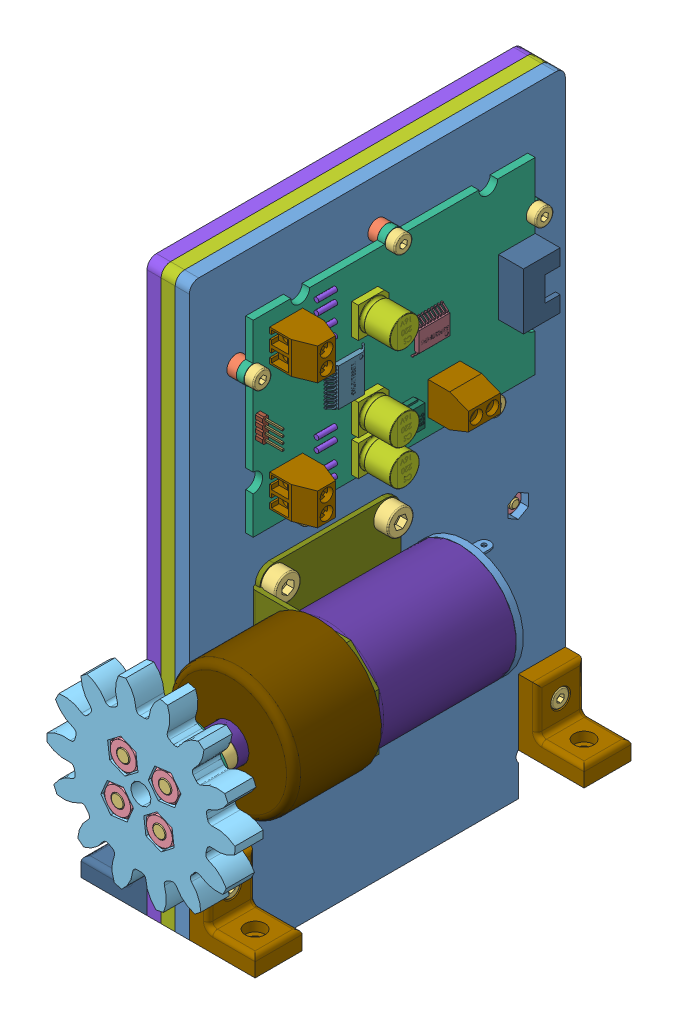
SolidWorks assembly moteur-complet, configuration Défaut. Lengths in mm.
Overall size (65.16 130 104.7).
92 component instances, 29 part files, 113 mates.
Components (placement in the parent):
- moteur-platine-1-4: moteur-platine-1 [Défaut] at (-59.9962 -68.9698 170) size (3 130 80)
- Grove button-1: Grove button [Défaut] at (-66.7015 -12.8903 110) x (0 -1 0) z (0 0 -1) size (20 11.6 23.6)
  - PCB grove 20x20-1: PCB grove 20x20 [Défaut] at (2.0795 1.2947 0) size (20 1.6 23.6)
  - 603 resistor 102-1: 603 resistor 102 [Default] at (2.0895 2.8947 -6.319) x (0 0 1) z (-1 0 0) size (2.36 0.62 1.03)
  - tactileswitch-CMS-1: tactileswitch-CMS [Default] at (-2.4169 2.8947 0.0035) x (0 0 1) z (-1 0 0) size (8.41 4.95 6.01)
  - Connecteur Grove (droit CMS)-1: Connecteur Grove (droit CMS) [Défaut] at (5.0795 2.8947 0) x (-1 0 0) z (0 1 0) size (6.5 14 10)
  - 603 resistor 102-2: 603 resistor 102 [Default] at (3.5895 2.8947 -6.319) x (0 0 1) z (-1 0 0) size (2.36 0.62 1.03)
- Grove I2C Motor driver TB6612FNG-1: Grove I2C Motor driver TB6612FNG [Défaut] at (-118.1962 28.5169 135.6463) x (0 0 1) z (1 0 0) size (64 44 12.2)
  - Plaque de base-1: Plaque de base [Défaut] at (-5.6463 -2.5133 63.2) size (64 44 1.6)
  - CS 220 16V-1: CS 220 16V [Défaut] at (0.1237 13.2167 64.8) x (1 0 0) z (0 -1 0) size (6.54 8.01 6.54)
  - CS 220 16V-2: CS 220 16V [Défaut] at (0.1237 5.6767 64.8) x (1 0 0) z (0 -1 0) size (6.54 8.01 6.54)
  - CS 220 16V-3: CS 220 16V [Défaut] at (0.1237 -12.2433 64.8) x (1 0 0) z (0 -1 0) size (6.54 8.01 6.54)
  - D1-1: D1 [Défaut] at (7.4081 5.2819 65.3) x (0 0.946795 -0.321836) z (1 0 0) size (1 1 4)
  - D1-2: D1 [Défaut] at (7.4081 7.7235 65.3) x (0 0.786026 0.618193) z (1 0 0) size (1 1 4)
  - D1-3: D1 [Défaut] at (7.4081 14.4025 65.3) x (0 0.953842 0.300308) z (1 0 0) size (1 1 4)
  - D1-4: D1 [Défaut] at (7.4081 11.9602 65.3) x (0 0.659384 0.751806) z (1 0 0) size (1 1 4)
  - D1-5: D1 [Défaut] at (7.4081 -17.5815 65.3) x (0 -0.999835 -0.018161) z (1 0 0) size (1 1 4)
  - D1-6: D1 [Défaut] at (7.4081 -14.133 65.3) x (0 0.806812 -0.590809) z (1 0 0) size (1 1 4)
  - D1-7: D1 [Défaut] at (7.4081 -11.4343 65.3) x (0 -0.166774 0.985995) z (1 0 0) size (1 1 4)
  - D1-8: D1 [Défaut] at (7.4081 -20.0356 65.3) x (0 0.962631 -0.270816) z (1 0 0) size (1 1 4)
  - bornier double-1: bornier double [Défaut] at (20.8537 7.1995 64.8) x (0 1 0) z (1 0 0) size (6.8 12.2 7)
  - bornier double-2: bornier double [Défaut] at (-12.8463 13.9867 64.8) x (-1 0 0) z (0 1 0) size (6.8 12.2 7)
  - bornier double-3: bornier double [Défaut] at (20.8537 -19.5133 64.8) x (0 1 0) z (1 0 0) size (6.8 12.2 7)
  - Grove Connecteur-1: Grove Connecteur [Défaut] at (-37.0963 -2.5133 64.05) x (1 0 0) z (0 -1 0) size (7.8 5.3 12)
  - Bloc 4 pins male-1: Bloc 4 pins male [Défaut] at (23.2493 -0.7812 63.276) x (0 -1 0) z (0 0 1) size (5.08 1.27 7.62)
    - Pin_cmi2c_Base-1: Pin_cmi2c_Base [Défaut] at (-0.1729 -0.0306 1.524) size (1.27 1.27 1.52)
    - Pin_cmi2c-1: Pin_cmi2c [Défaut] at (-0.1729 0.1472 -0.762) x (1 0 0) z (0 -1 0) size (0.36 7.62 0.36)
    - Pin_cmi2c-2: Pin_cmi2c [Défaut] at (1.0971 0.1472 -0.762) x (1 0 0) z (0 -1 0) size (0.36 7.62 0.36)
    - Pin_cmi2c-3: Pin_cmi2c [Défaut] at (2.3671 0.1472 -0.762) x (1 0 0) z (0 -1 0) size (0.36 7.62 0.36)
    - Pin_cmi2c-4: Pin_cmi2c [Défaut] at (3.6371 0.1472 -0.762) x (1 0 0) z (0 -1 0) size (0.36 7.62 0.36)
    - Pin_cmi2c_Base-2: Pin_cmi2c_Base [Défaut] at (1.0971 -0.0306 1.524) size (1.27 1.27 1.52)
    - Pin_cmi2c_Base-3: Pin_cmi2c_Base [Défaut] at (2.3671 -0.0306 1.524) size (1.27 1.27 1.52)
    - Pin_cmi2c_Base-4: Pin_cmi2c_Base [Défaut] at (3.6371 -0.0306 1.524) size (1.27 1.27 1.52)
  - Microcontroller 32F030F4P6-1: Microcontroller 32F030F4P6 [Défaut] at (-12.4961 -2.5519 65.5199) size (6.61 6.93 1.72)
  - Microcontroller TB6612FNG-1: Microcontroller TB6612FNG [Défaut] at (5.1421 -2.7086 65.5199) x (0 1 0) z (0 0 1) size (8 8.26 1.72)
  - PK13-1: PK13 [Défaut] at (-8.5328 11.2953 64.8) x (0 -1 0) z (-1 0 0) size (5.33 2 3.32)
- moteur MFA-1: moteur MFA [Défaut] at (-44.4916 -13.5198 141.6132) x (0 0 -1) z (0 -1 0) size (69.13 27.9 30)
  - moteur-support-1: moteur-support [Défaut] at (-14.3868 -12.5047 0) size (31 26.4 30)
  - moteur-corps-1: moteur-corps [Défaut] at (14.8132 1.8953 0) x (0 0 1) z (-1 0 0) size (24 24 62.63)
  - moteur-capuchon-1: moteur-capuchon [Défaut] at (-15.3868 1.8953 0) x (0 0 1) z (-1 0 0) size (27 27 18.7)
  - moteur-arriere-1: moteur-arriere [Défaut] at (16.3132 1.8953 0) x (0 0 1) z (-1 0 0) size (24 24 6.5)
- entretoise-grove-1: entretoise-grove [Défaut] at (-54.9962 51.0302 130) x (0 0.271539 0.962428) z (-1 0 0) size (4 4 2)
- entretoise-grove-2: entretoise-grove [Défaut] at (-54.9962 41.0302 100) x (0 0.358036 0.933708) z (-1 0 0) size (4 4 2)
- entretoise-grove-3: entretoise-grove [Défaut] at (-54.9962 41.0302 160) x (0 -0.42455 0.905404) z (-1 0 0) size (4 4 2)
- entretoise-grove-4: entretoise-grove [Défaut] at (-54.9962 11.0302 150) x (0 0 1) z (-1 0 0) size (4 4 2)
- entretoise-grove-5: entretoise-grove [Défaut] at (-54.9962 11.0302 110) x (0 0.014886 0.999889) z (-1 0 0) size (4 4 2)
- entretoise-grove-6: entretoise-grove [Défaut] at (-67.9962 -14.9698 120) x (0 0.014606 -0.999893) z (1 0 0) size (4 4 2)
- entretoise-grove-7: entretoise-grove [Défaut] at (-67.9962 -14.9698 100) x (0 0.432952 0.901417) z (1 0 0) size (4 4 2)
- vis-chc-1: vis-chc [Vis CHC M2x12] at (-69.5962 -14.9698 100) x (0 0.697993 -0.716105) z (0 0.716105 0.697993) size (3.8 14 3.8)
- vis-chc-2: vis-chc [Vis CHC M2x12] at (-69.5962 -14.9698 120) x (0 0.185382 -0.982666) z (0 0.982666 0.185382) size (3.8 14 3.8)
- vis-chc-3: vis-chc [Vis CHC M2x12] at (-53.3962 41.0302 100) x (0 0.381849 -0.924225) z (0 -0.924225 -0.381849) size (3.8 14 3.8)
- vis-chc-4: vis-chc [Vis CHC M2x12] at (-53.3962 51.0302 130) x (0 0.381849 -0.924225) z (0 -0.924225 -0.381849) size (3.8 14 3.8)
- vis-chc-5: vis-chc [Vis CHC M2x12] at (-53.3962 41.0302 160) x (0 0.381849 -0.924225) z (0 -0.924225 -0.381849) size (3.8 14 3.8)
- vis-chc-6: vis-chc [Vis CHC M2x12] at (-53.3962 11.0302 150) x (0 0.381849 -0.924225) z (0 -0.924225 -0.381849) size (3.8 14 3.8)
- vis-chc-7: vis-chc [Vis CHC M2x12] at (-53.3962 11.0302 110) x (0 0.381849 -0.924225) z (0 -0.924225 -0.381849) size (3.8 14 3.8)
- ecrou-h-2: ecrou-h [6007 HU M2] at (-59.9962 -14.9698 120) x (0 0.866025 0.5) z (0 -0.5 0.866025) size (4 1.6 4.62)
- ecrou-h-3: ecrou-h [6007 HU M2] at (-59.9962 -14.9698 100) x (0 0 1) z (0 -1 0) size (4 1.6 4.62)
- ecrou-h-4: ecrou-h [6007 HU M2] at (-64.5962 11.0302 110) x (0 0.866025 0.5) z (0 -0.5 0.866025) size (4 1.6 4.62)
- ecrou-h-5: ecrou-h [6007 HU M2] at (-64.5962 11.0302 150) x (0 0.866025 0.5) z (0 -0.5 0.866025) size (4 1.6 4.62)
- ecrou-h-6: ecrou-h [6007 HU M2] at (-64.5962 41.0302 160) x (0 0.866025 0.5) z (0 -0.5 0.866025) size (4 1.6 4.62)
- ecrou-h-7: ecrou-h [6007 HU M2] at (-64.5962 51.0302 130) x (0 0.866025 0.5) z (0 -0.5 0.866025) size (4 1.6 4.62)
- ecrou-h-8: ecrou-h [6007 HU M2] at (-64.5962 41.0302 100) x (0 0.866025 0.5) z (0 -0.5 0.866025) size (4 1.6 4.62)
- vis-chc-8: vis-chc [Vis CHC M3x10] at (-55.9962 -1.5198 129) x (0 0.773717 -0.633531) z (0 -0.633531 -0.773717) size (5.5 13 5.5)
- vis-chc-9: vis-chc [Vis CHC M3x10] at (-55.9962 -1.5198 153) x (0 0.483049 -0.875594) z (0 -0.875594 -0.483049) size (5.5 13 5.5)
- vis-chc-10: vis-chc [Vis CHC M3x10] at (-55.9962 -25.5198 153) x (0 0.381849 -0.924225) z (0 -0.924225 -0.381849) size (5.5 13 5.5)
- vis-chc-11: vis-chc [Vis CHC M3x10] at (-55.9962 -25.5198 129) x (0 0.381849 -0.924225) z (0 -0.924225 -0.381849) size (5.5 13 5.5)
- ecrou-h-9: ecrou-h [6012 HU M3] at (-65.3962 -1.5198 153) x (0 0.866025 0.5) z (0 -0.5 0.866025) size (5.5 2.4 6.35)
- ecrou-h-10: ecrou-h [6012 HU M3] at (-65.3962 -25.5198 153) x (0 0.866025 0.5) z (0 -0.5 0.866025) size (5.5 2.4 6.35)
- ecrou-h-11: ecrou-h [6012 HU M3] at (-65.3962 -25.5198 129) x (0 0.866025 -0.5) z (0 0.5 0.866025) size (5.5 2.4 6.35)
- ecrou-h-12: ecrou-h [6012 HU M3] at (-65.3962 -1.5198 129) x (0 0.866025 -0.5) z (0 0.5 0.866025) size (5.5 2.4 6.35)
- vis-chc-14: vis-chc [Vis CHC M2x16] at (-54.9962 -50.9698 95) x (0 -0.431797 -0.901971) z (0 -0.901971 0.431797) size (3.8 18 3.8)
- vis-chc-15: vis-chc [Vis CHC M2x16] at (-54.9962 -50.9698 165) x (0 0.381849 -0.924225) z (0 -0.924225 -0.381849) size (3.8 18 3.8)
- ecrou-h-15: ecrou-h [6007 HU M2] at (-69.5962 -50.9698 165) x (0 1 0) z (0 0 1) size (4 1.6 4.62)
- ecrou-h-16: ecrou-h [6007 HU M2] at (-69.5962 -50.9698 95) x (0 0.5 0.866025) z (0 -0.866025 0.5) size (4 1.6 4.62)
- engrenage-complet-1: engrenage-complet [Défaut] at (-43.0713 -13.4207 194.7) x (-0.795458 -0.606009 0) z (0 0 -1) size (39.32 40 13)
  - engrenage-1: engrenage [Défaut] at (1.0609 0.1936 0) size (39.32 40 6)
  - vis-chc-2: vis-chc [Vis CHC M3x10] at (6.0322 -0.3667 10) x (0.997256 0.074024 0) z (0.074024 -0.997256 0) size (5.5 13 5.5)
  - ecrou-h-1: ecrou-h [6012 HU M3] at (6.0322 -0.3667 0.1) x (1 0 0) z (0 1 0) size (5.5 2.4 6.35)
  - engrenage-moyeu-1: engrenage-moyeu [Défaut] at (-0.3178 -0.3667 7.5) x (0.707107 -0.707107 0) z (0 0 1) size (19 19 5)
  - vis-chc-3: vis-chc [Vis CHC M3x10] at (-0.3178 5.9833 10) x (0.997256 0.074024 0) z (0.074024 -0.997256 0) size (5.5 13 5.5)
  - vis-chc-4: vis-chc [Vis CHC M3x10] at (-6.6678 -0.3667 10) x (0.997256 0.074024 0) z (0.074024 -0.997256 0) size (5.5 13 5.5)
  - vis-chc-5: vis-chc [Vis CHC M3x10] at (-0.3178 -6.7167 10) x (0.997256 0.074024 0) z (0.074024 -0.997256 0) size (5.5 13 5.5)
  - ecrou-h-2: ecrou-h [6012 HU M3] at (-6.6678 -0.3667 0.1) x (0.5 0.866025 0) z (-0.866025 0.5 0) size (5.5 2.4 6.35)
  - ecrou-h-3: ecrou-h [6012 HU M3] at (-0.3178 5.9833 0.1) x (0.866025 0.5 0) z (-0.5 0.866025 0) size (5.5 2.4 6.35)
  - ecrou-h-4: ecrou-h [6012 HU M3] at (-0.3178 -6.7167 0.1) x (0.866025 0.5 0) z (-0.5 0.866025 0) size (5.5 2.4 6.35)
- moteur-platine-2-5: moteur-platine-2 [Défaut] at (-62.9962 -68.9698 170) size (3 130 80)
- moteur-platine-3-3: moteur-platine-3 [Défaut] at (-65.9962 -68.9698 170) size (3 130 80)
- equerre-3: equerre [Défaut] at (-56.9962 -59.9698 165) x (0 0 -1) z (1 0 0) size (10 14 14)
- equerre-2: equerre [Défaut] at (-56.9962 -59.9698 95) x (0 0 -1) z (1 0 0) size (10 14 14)
- equerre-ecrou-1: equerre-ecrou [Défaut] at (-65.9962 -59.9698 95) x (0 0 1) z (-1 0 0) size (10 14 14)
- equerre-ecrou-2: equerre-ecrou [Défaut] at (-65.9962 -59.9698 165) x (0 0 1) z (-1 0 0) size (10 14 14)
- vis-sthc-m3x5-1: vis-sthc-m3x5 [Défaut] at (-41.6585 -6.5829 187.2) x (-0.051839 0.007008 0.998631) z (0.133961 0.990987 0) size (3.08 3.15 5.22)
Mates (geometry in assembly coordinates):
- Coïncidente1: coincident anti-aligned: plane of moteur-platine-1-4 through (-56.9962 -61.1012 161.1314) normal (1 0 0); plane of moteur MFA-1/moteur-support-1 through (-56.9962 -25.5198 153) normal (-1 0 0)
- Coaxiale1: concentric anti-aligned: cylinder of moteur-platine-1-4 through (-59.9962 -1.5198 129) axis (1 0 0) radius 1.6; cylinder of moteur MFA-1/moteur-support-1 through (-30.5962 -1.5198 129) axis (-1 0 0) radius 1.65
- Coaxiale2: concentric anti-aligned: cylinder of moteur-platine-1-4 through (-59.9962 -25.5198 129) axis (1 0 0) radius 1.6; cylinder of moteur MFA-1/moteur-support-1 through (-30.5962 -25.5198 129) axis (-1 0 0) radius 1.65
- Parallèle1: parallel aligned: plane of moteur-platine-1-4 through (-56.9962 61.0302 90) normal (0 0 -1); plane of Grove I2C Motor driver TB6612FNG-1/Plaque de base-1 through (-53.3962 11.0302 100) normal (0 0 -1)
- Parallèle2: parallel aligned: plane of moteur-platine-1-4 through (-56.9962 61.0302 170) normal (0 1 0); plane of Grove I2C Motor driver TB6612FNG-1/Plaque de base-1 through (-53.3962 51.0302 132) normal (0 1 0)
- Coaxiale3: concentric anti-aligned: cylinder of Grove I2C Motor driver TB6612FNG-1/Plaque de base-1 through (-53.3962 11.0302 110) axis (-1 0 0) radius 1; cylinder of entretoise-grove-5 through (-56.9962 11.0302 110) axis (1 0 0) radius 1.2
- Coïncidente4: coincident anti-aligned: plane of Grove I2C Motor driver TB6612FNG-1/Plaque de base-1 through (-54.9962 21.0302 100) normal (-1 0 0); plane of entretoise-grove-5 through (-54.9962 11.0302 110) normal (1 0 0)
- Coaxiale4: concentric anti-aligned: cylinder of Grove I2C Motor driver TB6612FNG-1/Plaque de base-1 through (-53.3962 11.0302 150) axis (-1 0 0) radius 1; cylinder of entretoise-grove-4 through (-56.9962 11.0302 150) axis (1 0 0) radius 1.2
- Coïncidente5: coincident anti-aligned: plane of Grove I2C Motor driver TB6612FNG-1/Plaque de base-1 through (-54.9962 21.0302 100) normal (-1 0 0); plane of entretoise-grove-4 through (-54.9962 11.0302 150) normal (1 0 0)
- Coaxiale5: concentric anti-aligned: cylinder of Grove I2C Motor driver TB6612FNG-1/Plaque de base-1 through (-53.3962 41.0302 100) axis (-1 0 0) radius 1; cylinder of entretoise-grove-2 through (-56.9962 41.0302 100) axis (1 0 0) radius 1.2
- Coïncidente6: coincident anti-aligned: plane of Grove I2C Motor driver TB6612FNG-1/Plaque de base-1 through (-54.9962 21.0302 100) normal (-1 0 0); plane of entretoise-grove-2 through (-54.9962 41.0302 100) normal (1 0 0)
- Coaxiale6: concentric anti-aligned: cylinder of Grove I2C Motor driver TB6612FNG-1/Plaque de base-1 through (-53.3962 41.0302 160) axis (-1 0 0) radius 1; cylinder of entretoise-grove-3 through (-56.9962 41.0302 160) axis (1 0 0) radius 1.2
- Coïncidente7: coincident anti-aligned: plane of Grove I2C Motor driver TB6612FNG-1/Plaque de base-1 through (-54.9962 21.0302 100) normal (-1 0 0); plane of entretoise-grove-3 through (-54.9962 41.0302 160) normal (1 0 0)
- Coaxiale7: concentric anti-aligned: cylinder of Grove I2C Motor driver TB6612FNG-1/Plaque de base-1 through (-53.3962 51.0302 130) axis (-1 0 0) radius 1; cylinder of entretoise-grove-1 through (-56.9962 51.0302 130) axis (1 0 0) radius 1.2
- Coïncidente8: coincident anti-aligned: plane of Grove I2C Motor driver TB6612FNG-1/Plaque de base-1 through (-54.9962 21.0302 100) normal (-1 0 0); plane of entretoise-grove-1 through (-54.9962 51.0302 130) normal (1 0 0)
- Coïncidente9: coincident anti-aligned: plane of moteur-platine-1-4 through (-56.9962 -61.1012 161.1314) normal (1 0 0); plane of entretoise-grove-3 through (-56.9962 41.0302 160) normal (-1 0 0)
- Coaxiale8: concentric aligned: cylinder of moteur-platine-1-4 through (-59.9962 11.0302 150) axis (1 0 0) radius 1.1; cylinder of entretoise-grove-4 through (-56.9962 11.0302 150) axis (1 0 0) radius 1.2
- Coaxiale9: concentric anti-aligned: cylinder of Grove button-1/PCB grove 20x20-1 through (-69.5962 -14.9698 120) axis (1 0 0) radius 1.1; cylinder of entretoise-grove-6 through (-65.9962 -14.9698 120) axis (-1 0 0) radius 1.2
- Coaxiale10: concentric anti-aligned: cylinder of Grove button-1/PCB grove 20x20-1 through (-69.5962 -14.9698 100) axis (1 0 0) radius 1.1; cylinder of entretoise-grove-7 through (-65.9962 -14.9698 100) axis (-1 0 0) radius 1.2
- Coïncidente11: coincident anti-aligned: plane of Grove button-1/PCB grove 20x20-1 through (-67.9962 -14.9698 110) normal (1 0 0); plane of entretoise-grove-7 through (-67.9962 -14.9698 100) normal (-1 0 0)
- Coaxiale13: concentric anti-aligned: cylinder of moteur MFA-1/moteur-corps-1 through (-42.5962 -13.5198 189.43) axis (0 0 -1) radius 2; cylinder of engrenage-complet-1/engrenage-bague_arret-1 through (-42.5962 -13.5198 179.93) axis (0 0 1) radius 2.05
- Distance1: distance = 0.5 mm anti-aligned: plane of engrenage-complet-1/engrenage-bague_arret-1 through (-42.5962 -13.5198 179.93) normal (0 0 -1); plane of moteur MFA-1/moteur-corps-1 through (-42.5962 -13.5198 179.43) normal (0 0 1)
- Coïncidente12: coincident anti-aligned: plane of moteur-platine-1-4 through (-59.9962 -61.1012 161.1314) normal (-1 0 0); plane of moteur-platine-2-5 through (-59.9962 -61.1012 161.1314) normal (1 0 0)
- Coïncidente13: coincident aligned: plane of moteur-platine-1-4 through (-56.9962 61.0302 170) normal (0 1 0); plane of moteur-platine-2-5 through (-59.9962 61.0302 170) normal (0 1 0)
- Coïncidente14: coincident aligned: plane of moteur-platine-1-4 through (-56.9962 61.0302 90) normal (0 0 -1); plane of moteur-platine-2-5 through (-59.9962 61.0302 90) normal (0 0 -1)
- Coïncidente15: coincident anti-aligned: plane of moteur-platine-2-5 through (-62.9962 -61.1012 161.1314) normal (-1 0 0); plane of moteur-platine-3-3 through (-62.9962 -61.1012 161.1314) normal (1 0 0)
- Coïncidente16: coincident aligned: plane of moteur-platine-2-5 through (-59.9962 61.0302 170) normal (0 1 0); plane of moteur-platine-3-3 through (-62.9962 61.0302 170) normal (0 1 0)
- Coïncidente17: coincident aligned: plane of moteur-platine-1-4 through (-56.9962 61.0302 90) normal (0 0 -1); plane of moteur-platine-3-3 through (-62.9962 61.0302 90) normal (0 0 -1)
- Coïncidente18: coincident anti-aligned: plane of entretoise-grove-7 through (-65.9962 -14.9698 100) normal (1 0 0); plane of moteur-platine-3-3 through (-65.9962 -61.1012 161.1314) normal (-1 0 0)
- Coïncidente19: coincident anti-aligned: plane of entretoise-grove-6 through (-65.9962 -14.9698 120) normal (1 0 0); plane of moteur-platine-3-3 through (-65.9962 -61.1012 161.1314) normal (-1 0 0)
- Coïncidente21: coincident anti-aligned: plane of Grove button-1/PCB grove 20x20-1 through (-69.5962 -14.9698 110) normal (-1 0 0); plane of vis-chc-2 through (-69.5962 -14.9698 120) normal (1 0 0)
- Coaxiale15: concentric aligned: cylinder of vis-chc-2 through (-57.5962 -14.9698 120) axis (-1 0 0) radius 1; cylinder of ecrou-h-2 through (-58.3962 -14.9698 120) axis (-1 0 0) radius 0.7835
- Parallèle4: parallel aligned: plane of moteur-platine-1-4 through (-56.9962 61.0302 90) normal (0 0 -1); plane of ecrou-h-2 through (-58.3962 -13.8151 118) normal (0 0 -1)
- Coïncidente25: coincident anti-aligned: plane of Grove button-1/PCB grove 20x20-1 through (-69.5962 -14.9698 110) normal (-1 0 0); plane of vis-chc-1 through (-69.5962 -14.9698 100) normal (1 0 0)
- Coaxiale17: concentric aligned: cylinder of vis-chc-1 through (-57.5962 -14.9698 100) axis (-1 0 0) radius 1; cylinder of ecrou-h-3 through (-58.3962 -14.9698 100) axis (-1 0 0) radius 0.7835
- Parallèle5: parallel aligned: plane of moteur-platine-1-4 through (-56.9962 61.0302 90) normal (0 0 -1); plane of ecrou-h-3 through (-58.3962 -13.8151 98) normal (0 0 -1)
- Coaxiale18: concentric anti-aligned: cylinder of Grove I2C Motor driver TB6612FNG-1/Plaque de base-1 through (-53.3962 11.0302 110) axis (-1 0 0) radius 1; cylinder of vis-chc-7 through (-65.3962 11.0302 110) axis (1 0 0) radius 1
- Coaxiale19: concentric anti-aligned: cylinder of Grove I2C Motor driver TB6612FNG-1/Plaque de base-1 through (-53.3962 11.0302 150) axis (-1 0 0) radius 1; cylinder of vis-chc-6 through (-65.3962 11.0302 150) axis (1 0 0) radius 1
- Coaxiale20: concentric anti-aligned: cylinder of Grove I2C Motor driver TB6612FNG-1/Plaque de base-1 through (-53.3962 41.0302 160) axis (-1 0 0) radius 1; cylinder of vis-chc-5 through (-65.3962 41.0302 160) axis (1 0 0) radius 1
- Coaxiale21: concentric anti-aligned: cylinder of Grove I2C Motor driver TB6612FNG-1/Plaque de base-1 through (-53.3962 51.0302 130) axis (-1 0 0) radius 1; cylinder of vis-chc-4 through (-65.3962 51.0302 130) axis (1 0 0) radius 1
- Coaxiale22: concentric anti-aligned: cylinder of Grove I2C Motor driver TB6612FNG-1/Plaque de base-1 through (-53.3962 41.0302 100) axis (-1 0 0) radius 1; cylinder of vis-chc-3 through (-65.3962 41.0302 100) axis (1 0 0) radius 1
- Coïncidente28: coincident anti-aligned: plane of Grove I2C Motor driver TB6612FNG-1/Plaque de base-1 through (-53.3962 21.0302 100) normal (1 0 0); plane of vis-chc-3 through (-53.3962 41.0302 100) normal (-1 0 0)
- Coïncidente29: coincident anti-aligned: plane of Grove I2C Motor driver TB6612FNG-1/Plaque de base-1 through (-53.3962 21.0302 100) normal (1 0 0); plane of vis-chc-4 through (-53.3962 51.0302 130) normal (-1 0 0)
- Coïncidente30: coincident anti-aligned: plane of Grove I2C Motor driver TB6612FNG-1/Plaque de base-1 through (-53.3962 21.0302 100) normal (1 0 0); plane of vis-chc-5 through (-53.3962 41.0302 160) normal (-1 0 0)
- Coïncidente31: coincident anti-aligned: plane of Grove I2C Motor driver TB6612FNG-1/Plaque de base-1 through (-53.3962 21.0302 100) normal (1 0 0); plane of vis-chc-6 through (-53.3962 11.0302 150) normal (-1 0 0)
- Coïncidente32: coincident anti-aligned: plane of Grove I2C Motor driver TB6612FNG-1/Plaque de base-1 through (-53.3962 21.0302 100) normal (1 0 0); plane of vis-chc-7 through (-53.3962 11.0302 110) normal (-1 0 0)
- Coaxiale23: concentric anti-aligned: cylinder of vis-chc-7 through (-65.3962 11.0302 110) axis (1 0 0) radius 1; cylinder of ecrou-h-4 through (-62.9962 11.0302 110) axis (-1 0 0) radius 0.7835
- Coaxiale24: concentric anti-aligned: cylinder of vis-chc-3 through (-65.3962 41.0302 100) axis (1 0 0) radius 1; cylinder of ecrou-h-8 through (-62.9962 41.0302 100) axis (-1 0 0) radius 0.7835
- Coaxiale25: concentric anti-aligned: cylinder of vis-chc-4 through (-65.3962 51.0302 130) axis (1 0 0) radius 1; cylinder of ecrou-h-7 through (-62.9962 51.0302 130) axis (-1 0 0) radius 0.7835
- Coaxiale26: concentric anti-aligned: cylinder of vis-chc-5 through (-65.3962 41.0302 160) axis (1 0 0) radius 1; cylinder of ecrou-h-6 through (-62.9962 41.0302 160) axis (-1 0 0) radius 0.7835
- Coaxiale27: concentric anti-aligned: cylinder of vis-chc-6 through (-65.3962 11.0302 150) axis (1 0 0) radius 1; cylinder of ecrou-h-5 through (-62.9962 11.0302 150) axis (-1 0 0) radius 0.7835
- Parallèle6: parallel aligned: plane of moteur-platine-3-3 through (-62.9962 -59.9698 170) normal (0 0 1); plane of ecrou-h-6 through (-62.9962 39.8755 162) normal (0 0 1)
- Parallèle7: parallel aligned: plane of moteur-platine-3-3 through (-62.9962 -59.9698 170) normal (0 0 1); plane of ecrou-h-7 through (-62.9962 49.8755 132) normal (0 0 1)
- Parallèle8: parallel aligned: plane of moteur-platine-3-3 through (-62.9962 -59.9698 170) normal (0 0 1); plane of ecrou-h-8 through (-62.9962 39.8755 102) normal (0 0 1)
- Parallèle9: parallel aligned: plane of moteur-platine-3-3 through (-62.9962 -59.9698 170) normal (0 0 1); plane of ecrou-h-5 through (-62.9962 9.8755 152) normal (0 0 1)
- Parallèle10: parallel aligned: plane of moteur-platine-3-3 through (-62.9962 -59.9698 170) normal (0 0 1); plane of ecrou-h-4 through (-62.9962 9.8755 112) normal (0 0 1)
- Coaxiale28: concentric anti-aligned: cylinder of moteur MFA-1/moteur-support-1 through (-30.5962 -1.5198 153) axis (-1 0 0) radius 1.65; cylinder of vis-chc-9 through (-65.9962 -1.5198 153) axis (1 0 0) radius 1.5
- Coaxiale29: concentric anti-aligned: cylinder of moteur MFA-1/moteur-support-1 through (-30.5962 -1.5198 129) axis (-1 0 0) radius 1.65; cylinder of vis-chc-8 through (-65.9962 -1.5198 129) axis (1 0 0) radius 1.5
- Coaxiale30: concentric anti-aligned: cylinder of moteur MFA-1/moteur-support-1 through (-30.5962 -25.5198 129) axis (-1 0 0) radius 1.65; cylinder of vis-chc-11 through (-65.9962 -25.5198 129) axis (1 0 0) radius 1.5
- Coaxiale31: concentric anti-aligned: cylinder of moteur MFA-1/moteur-support-1 through (-30.5962 -25.5198 153) axis (-1 0 0) radius 1.65; cylinder of vis-chc-10 through (-65.9962 -25.5198 153) axis (1 0 0) radius 1.5
- Coïncidente43: coincident anti-aligned: plane of moteur MFA-1/moteur-support-1 through (-55.9962 -29.752 156) normal (1 0 0); plane of vis-chc-11 through (-55.9962 -25.5198 129) normal (-1 0 0)
- Coïncidente44: coincident aligned: plane of moteur MFA-1/moteur-support-1 through (-55.9962 -29.752 156) normal (1 0 0); circle of vis-chc-10
- Coïncidente45: coincident anti-aligned: plane of moteur MFA-1/moteur-support-1 through (-55.9962 -29.752 156) normal (1 0 0); plane of vis-chc-8 through (-55.9962 -1.5198 129) normal (-1 0 0)
- Coïncidente46: coincident anti-aligned: plane of moteur MFA-1/moteur-support-1 through (-55.9962 -29.752 156) normal (1 0 0); plane of vis-chc-9 through (-55.9962 -1.5198 153) normal (-1 0 0)
- Coaxiale32: concentric anti-aligned: cylinder of vis-chc-8 through (-65.9962 -1.5198 129) axis (1 0 0) radius 1.5; cylinder of ecrou-h-12 through (-62.9962 -1.5198 129) axis (-1 0 0) radius 1.2295
- Coaxiale33: concentric anti-aligned: cylinder of vis-chc-10 through (-65.9962 -25.5198 153) axis (1 0 0) radius 1.5; cylinder of ecrou-h-10 through (-62.9962 -25.5198 153) axis (-1 0 0) radius 1.2295
- Coaxiale34: concentric anti-aligned: cylinder of vis-chc-9 through (-65.9962 -1.5198 153) axis (1 0 0) radius 1.5; cylinder of ecrou-h-9 through (-62.9962 -1.5198 153) axis (-1 0 0) radius 1.2295
- Coaxiale35: concentric anti-aligned: cylinder of vis-chc-11 through (-65.9962 -25.5198 129) axis (1 0 0) radius 1.5; cylinder of ecrou-h-11 through (-62.9962 -25.5198 129) axis (-1 0 0) radius 1.2295
- Parallèle11: parallel aligned: plane of moteur-platine-3-3 through (-62.9962 -59.9698 170) normal (0 0 1); plane of ecrou-h-10 through (-62.9962 -27.1075 155.75) normal (0 0 1)
- Parallèle12: parallel aligned: plane of moteur-platine-3-3 through (-62.9962 -59.9698 170) normal (0 0 1); plane of ecrou-h-11 through (-62.9962 -27.1075 131.75) normal (0 0 1)
- Parallèle13: parallel aligned: plane of moteur-platine-3-3 through (-62.9962 -59.9698 170) normal (0 0 1); plane of ecrou-h-12 through (-62.9962 -3.1075 131.75) normal (0 0 1)
- Parallèle14: parallel aligned: plane of moteur-platine-3-3 through (-62.9962 -59.9698 170) normal (0 0 1); plane of ecrou-h-9 through (-62.9962 -3.1075 155.75) normal (0 0 1)
- Coïncidente62: coincident anti-aligned: plane of moteur-platine-1-4 through (-56.9962 -61.1012 161.1314) normal (1 0 0); plane of equerre-2 through (-56.9962 -59.9698 95) normal (-1 0 0)
- Coaxiale41: concentric aligned: cylinder of moteur-platine-1-4 through (-59.9962 -50.9698 95) axis (1 0 0) radius 1.1; cylinder of equerre-2 through (-56.9962 -50.9698 95) axis (1 0 0) radius 1.1
- Coïncidente63: coincident aligned: plane of moteur-platine-1-4 through (-56.9962 -59.9698 97.7373) normal (0 -1 0); plane of equerre-2 through (-52.9962 -59.9698 100) normal (0 -1 0)
- Coaxiale42: concentric aligned: cylinder of moteur-platine-1-4 through (-59.9962 -50.9698 165) axis (1 0 0) radius 1.1; cylinder of equerre-3 through (-56.9962 -50.9698 165) axis (1 0 0) radius 1.1
- Coïncidente64: coincident aligned: plane of moteur-platine-1-4 through (-56.9962 -59.9698 162.2627) normal (0 -1 0); plane of equerre-3 through (-52.9962 -59.9698 170) normal (0 -1 0)
- Coïncidente65: coincident anti-aligned: plane of moteur-platine-1-4 through (-56.9962 -61.1012 161.1314) normal (1 0 0); plane of equerre-3 through (-56.9962 -59.9698 165) normal (-1 0 0)
- Coaxiale43: concentric aligned: cylinder of vis-chc-15 through (-70.9962 -50.9698 165) axis (1 0 0) radius 1; cylinder of equerre-3 through (-56.9962 -50.9698 165) axis (1 0 0) radius 1.1
- Coïncidente66: coincident anti-aligned: plane of vis-chc-15 through (-54.9962 -50.9698 165) normal (-1 0 0); plane of equerre-3 through (-54.9962 -50.9698 165) normal (1 0 0)
- Coaxiale44: concentric aligned: cylinder of vis-chc-14 through (-70.9962 -50.9698 95) axis (1 0 0) radius 1; cylinder of equerre-2 through (-56.9962 -50.9698 95) axis (1 0 0) radius 1.1
- Coïncidente67: coincident anti-aligned: plane of vis-chc-14 through (-54.9962 -50.9698 95) normal (-1 0 0); plane of equerre-2 through (-54.9962 -50.9698 95) normal (1 0 0)
- Coïncidente68: coincident anti-aligned: plane of moteur-platine-3-3 through (-65.9962 -61.1012 161.1314) normal (-1 0 0); plane of equerre-ecrou-2 through (-65.9962 -59.9698 165) normal (1 0 0)
- Coïncidente69: coincident anti-aligned: plane of moteur-platine-3-3 through (-65.9962 -61.1012 161.1314) normal (-1 0 0); plane of equerre-ecrou-1 through (-65.9962 -59.9698 95) normal (1 0 0)
- Coïncidente70: coincident aligned: plane of moteur-platine-3-3 through (-62.9962 -59.9698 97.7373) normal (0 -1 0); plane of equerre-ecrou-1 through (-69.9962 -59.9698 90) normal (0 -1 0)
- Coïncidente71: coincident aligned: plane of moteur-platine-3-3 through (-62.9962 -59.9698 97.7373) normal (0 -1 0); plane of equerre-ecrou-2 through (-69.9962 -59.9698 160) normal (0 -1 0)
- Coaxiale45: concentric anti-aligned: cylinder of vis-chc-14 through (-70.9962 -50.9698 95) axis (1 0 0) radius 1; cylinder of equerre-ecrou-1 through (-65.9962 -50.9698 95) axis (-1 0 0) radius 1.1
- Coaxiale46: concentric anti-aligned: cylinder of vis-chc-15 through (-70.9962 -50.9698 165) axis (1 0 0) radius 1; cylinder of equerre-ecrou-2 through (-65.9962 -50.9698 165) axis (-1 0 0) radius 1.1
- Coaxiale47: concentric anti-aligned: cylinder of vis-chc-15 through (-70.9962 -50.9698 165) axis (1 0 0) radius 1; cylinder of ecrou-h-15 through (-67.9962 -50.9698 165) axis (-1 0 0) radius 0.7835
- Parallèle18: parallel anti-aligned: plane of ecrou-h-15 through (-67.9962 -48.9698 166.1547) normal (0 1 0); plane of equerre-ecrou-2 through (-67.9962 -48.8047 166.25) normal (0 -1 0)
- Coïncidente73: coincident anti-aligned: plane of ecrou-h-15 through (-67.9962 -48.9698 163.8453) normal (1 0 0); plane of equerre-ecrou-2 through (-67.9962 -59.9698 165) normal (-1 0 0)
- Coaxiale49: concentric anti-aligned: cylinder of vis-chc-14 through (-70.9962 -50.9698 95) axis (1 0 0) radius 1; cylinder of ecrou-h-16 through (-67.9962 -50.9698 95) axis (-1 0 0) radius 0.7835
- Parallèle19: parallel anti-aligned: plane of ecrou-h-16 through (-67.9962 -48.9698 96.1547) normal (0 1 0); plane of equerre-ecrou-1 through (-67.9962 -48.8047 96.25) normal (0 -1 0)
- Coïncidente75: coincident anti-aligned: plane of ecrou-h-16 through (-67.9962 -48.9698 96.1547) normal (1 0 0); plane of equerre-ecrou-1 through (-67.9962 -59.9698 95) normal (-1 0 0)
- Coïncidente76: coincident anti-aligned: plane of ecrou-h-6 through (-62.9962 43.3396 160) normal (1 0 0); plane of moteur-platine-2-5 through (-62.9962 -61.1012 161.1314) normal (-1 0 0)
- Coïncidente77: coincident anti-aligned: plane of ecrou-h-5 through (-62.9962 13.3396 150) normal (1 0 0); plane of moteur-platine-2-5 through (-62.9962 -61.1012 161.1314) normal (-1 0 0)
- Coïncidente78: coincident anti-aligned: plane of ecrou-h-4 through (-62.9962 13.3396 110) normal (1 0 0); plane of moteur-platine-2-5 through (-62.9962 -61.1012 161.1314) normal (-1 0 0)
- Coïncidente79: coincident anti-aligned: plane of ecrou-h-8 through (-62.9962 43.3396 100) normal (1 0 0); plane of moteur-platine-2-5 through (-62.9962 -61.1012 161.1314) normal (-1 0 0)
- Coïncidente80: coincident anti-aligned: plane of ecrou-h-7 through (-62.9962 53.3396 130) normal (1 0 0); plane of moteur-platine-2-5 through (-62.9962 -61.1012 161.1314) normal (-1 0 0)
- Coïncidente81: coincident anti-aligned: plane of ecrou-h-12 through (-62.9962 0.0679 126.25) normal (1 0 0); plane of moteur-platine-2-5 through (-62.9962 -61.1012 161.1314) normal (-1 0 0)
- Coïncidente82: coincident anti-aligned: plane of ecrou-h-11 through (-62.9962 -23.9321 126.25) normal (1 0 0); plane of moteur-platine-2-5 through (-62.9962 -61.1012 161.1314) normal (-1 0 0)
- Coïncidente83: coincident anti-aligned: plane of ecrou-h-10 through (-62.9962 -22.3444 153) normal (1 0 0); plane of moteur-platine-2-5 through (-62.9962 -61.1012 161.1314) normal (-1 0 0)
- Coïncidente84: coincident anti-aligned: plane of ecrou-h-9 through (-62.9962 1.6556 153) normal (1 0 0); plane of moteur-platine-2-5 through (-62.9962 -61.1012 161.1314) normal (-1 0 0)
- Coaxiale50: concentric anti-aligned: cylinder of vis-chc-2 through (-57.5962 -14.9698 120) axis (-1 0 0) radius 1; cylinder of moteur-platine-3-3 through (-65.9962 -14.9698 120) axis (1 0 0) radius 1
- Coaxiale51: concentric anti-aligned: cylinder of vis-chc-1 through (-57.5962 -14.9698 100) axis (-1 0 0) radius 1; cylinder of moteur-platine-3-3 through (-65.9962 -14.9698 100) axis (1 0 0) radius 1
- Coïncidente85: coincident anti-aligned: plane of ecrou-h-3 through (-59.9962 -13.8151 102) normal (-1 0 0); plane of moteur-platine-2-5 through (-59.9962 -61.1012 161.1314) normal (1 0 0)
- Coïncidente86: coincident anti-aligned: plane of ecrou-h-2 through (-59.9962 -12.6604 120) normal (-1 0 0); plane of moteur-platine-2-5 through (-59.9962 -61.1012 161.1314) normal (1 0 0)
- Coaxiale52: concentric anti-aligned: cylinder of Grove button-1/PCB grove 20x20-1 through (-69.5962 -14.9698 100) axis (1 0 0) radius 1.1; cylinder of vis-chc-1 through (-57.5962 -14.9698 100) axis (-1 0 0) radius 1
- Coaxiale53: concentric anti-aligned: cylinder of Grove button-1/PCB grove 20x20-1 through (-69.5962 -14.9698 120) axis (1 0 0) radius 1.1; cylinder of vis-chc-2 through (-57.5962 -14.9698 120) axis (-1 0 0) radius 1
- Coaxiale54: concentric aligned: cylinder of engrenage-complet-1/engrenage-moyeu-1 through (-40.4528 2.336 187.2) axis (-0.133961 -0.990987 0) radius 1.5; cone of vis-sthc-m3x5-1 through (-42.2948 -11.2901 187.2) axis (-0.133961 -0.990987 0)
- Coaxiale55: concentric anti-aligned: cylinder of moteur MFA-1/moteur-corps-1 through (-42.5962 -13.5198 189.43) axis (0 0 -1) radius 2; cylinder of engrenage-complet-1/engrenage-moyeu-1 through (-42.5962 -13.5198 184.7) axis (0 0 1) radius 2
- Tangent1: tangent anti-aligned: cylinder of moteur MFA-1/moteur-corps-1 through (-42.5962 -13.5198 189.43) axis (0 0 -1) radius 2; plane of vis-sthc-m3x5-1 through (-42.3283 -11.5378 187.2) normal (-0.133961 -0.990987 0)
- Distance2: distance = 13 mm anti-aligned: plane of engrenage-complet-1/engrenage-1 through (-42.5962 -13.5198 188.7) normal (0 0 -1); plane of moteur MFA-1/moteur-capuchon-1 through (-42.5962 -13.5198 175.7) normal (0 0 1)
